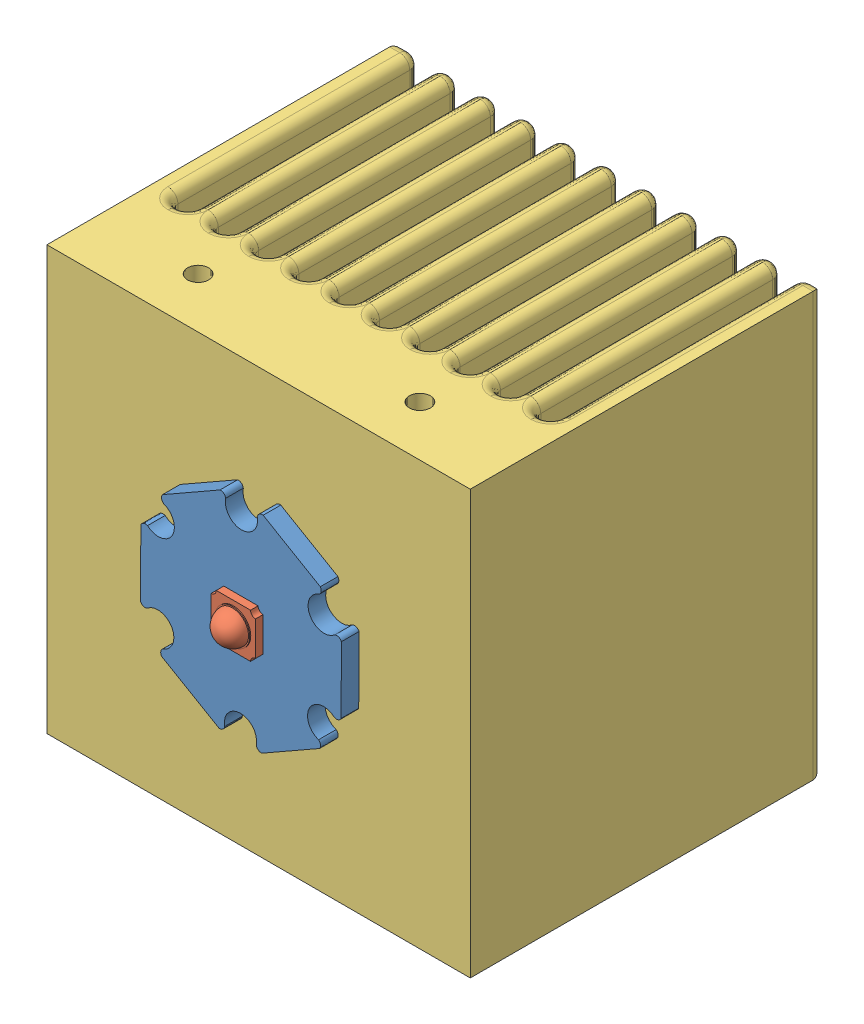
SolidWorks assembly chlazenaLED, configuration Výchozí. Lengths in mm.
Overall size (42 42 39.15).
3 component instances, 3 part files, 4 mates.
Components (placement in the parent):
- podlozkaLED-1: podlozkaLED [Výchozí] at (14.5961 -2.7013 2.65) x (0.98934 0.145626 0) z (0 0 1) size (20.67 20.93 1.75)
- LED-1: LED [Výchozí] at (49.2496 -34.7682 4.4) size (4.4 4.4 2.4)
- chladic-1: chladic [Výchozí] at (40.6795 -8.663 -7.35) size (42 42 35)
Mates (geometry in assembly coordinates):
- Sjednocená7: coincident anti-aligned: plane of podlozkaLED-1 through (14.5961 -2.7013 4.4) normal (0 0 1); plane of LED-1 through (1.4983 2.311 4.4) normal (0 0 -1)
- Sjednocená8: coincident: point of podlozkaLED-1; point of LED-1
- Sjednocená9: coincident anti-aligned: plane of podlozkaLED-1 through (14.5961 -2.7013 2.65) normal (0 0 -1); plane of chladic-1 through (40.6795 -8.663 2.65) normal (0 0 1)
- Sjednocená10: coincident: point of podlozkaLED-1; point of chladic-1
